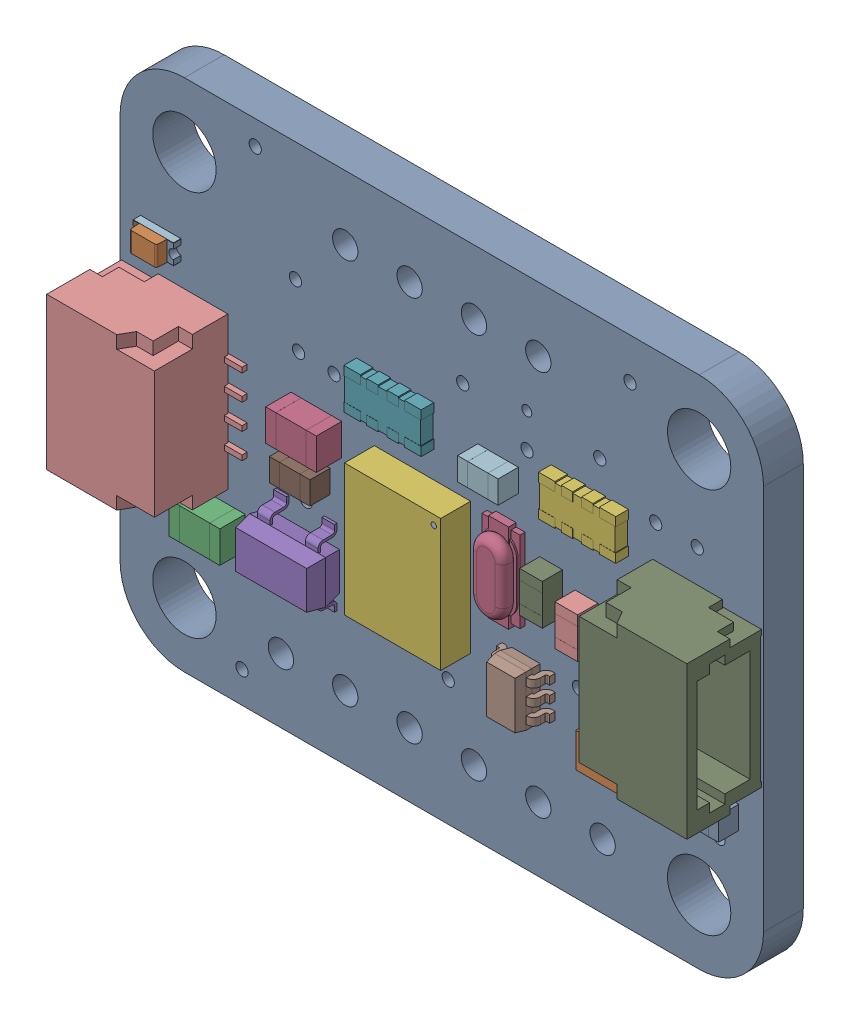
SolidWorks assembly 4646 BNO055 Stemma, configuration Default. Lengths in mm.
Overall size (25.4 20.32 4.53).
18 component instances, 11 part files, 0 mates.
Components (placement in the parent):
- Board-1: Board [Default] at origin size (25.4 20.32 1.57)
- BNO055-1: BNO055 [Default] at (11.938 8.89 1.57) x (0 -1 0) z (0 0 1) size (5.2 3.8 1.18)
- 10K-1: 10K [Default] at (17.018 10.16 1.57) x (0 1 0) z (0 0 1) size (1.6 0.9 0.8)
- 10K-2: 10K [Default] at (18.415 9.716 1.57) x (0 -1 0) z (0 0 1) size (1.6 0.9 0.8)
- 10K-3: 10K [Default] at (7.493 9.398 1.57) size (1.6 0.9 0.8)
- 10K-4: 10K [Default] at (14.922 13.144 1.57) size (1.6 0.9 0.8)
- 10K-5: 10K [Default] at (23.622 5.969 1.57) x (-1 0 0) z (0 0 1) size (1.6 0.9 0.8)
- 1n4148-1: 1n4148 [Default] at (19.939 6.16 1.57) size (2.7 1.35 1.1)
- 10uF-1: 10uF [Default] at (3.937 5.969 1.57) x (-1 0 0) z (0 0 1) size (2 1.25 1)
- 10uF-2: 10uF [Default] at (7.747 11.049 1.57) x (-1 0 0) z (0 0 1) size (2 1.25 1)
- AP2112K-3.3-1: AP2112K-3.3 [Default] at (7.366 6.604 1.57) size (3 3 1.4)
- 10K_1-1: 10K_1 [Default] at (18.542 13.526 1.57) x (-1 0 0) z (0 0 1) size (3.05 1.6 0.5)
- 10K_1-2: 10K_1 [Default] at (10.858 13.335 1.57) size (3.05 1.6 0.5)
- BSS138-1: BSS138 [Default] at (16.129 6.477 1.57) x (0 1 0) z (0 0 1) size (2 2.1 1.1)
- STEMMA_I2C_QT-1: STEMMA_I2C_QT [Default] at (22.86 10.16 1.57) x (0 1 0) z (0 0 1) size (6 4.95 2.96)
- STEMMA_I2C_QT-2: STEMMA_I2C_QT [Default] at (2.54 10.16 1.57) x (0 -1 0) z (0 0 1) size (6 4.95 2.96)
- GREEN-1: GREEN [Default] at (1.613 14.364 1.57) x (0 1 0) z (0 0 1) size (0.79 1.61 0.71)
- 32.768-1: 32.768 [Default] at (15.24 9.906 1.57) x (0 -1 0) z (0 0 1) size (3.5 1.5 0.8)
